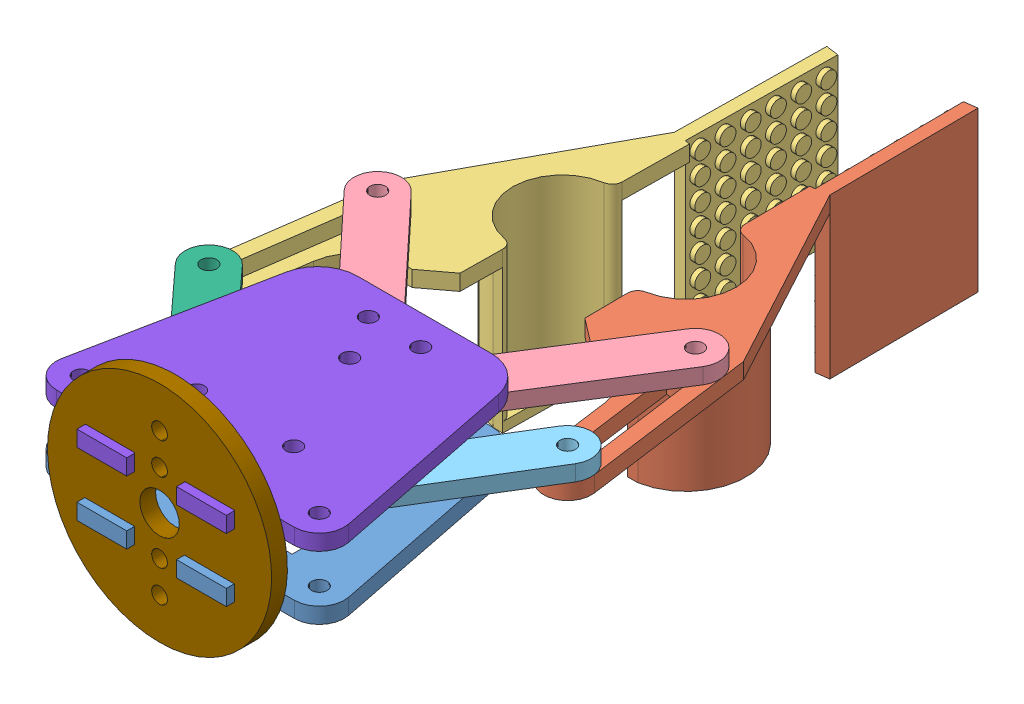
SolidWorks assembly Gripper, configuration Predeterminado. Lengths in mm.
Overall size (91.5 56.15 152.9).
15 component instances, 11 part files, 33 mates.
Components (placement in the parent):
- Base grip-1: Base grip [Predeterminado] at (-28.7905 -8.0804 25) size (57.8 3.17 54.76)
- Gripp4-3: Gripp4 [Predeterminado] at (19.4575 -1.7304 -56.7394) x (-0.990815 0 0.135226) z (0.135226 0 0.990815) size (24.38 32 109.52)
- Gripp3-3: Gripp3 [Predeterminado] at (-23.0143 -4.9054 -52.0769) x (0.99023 0 0.139447) z (-0.139447 0 0.99023) size (24.38 32 109.76)
- eslabon dos-1: eslabon dos [Predeterminado] at (13.1017 -1.7304 -38.4567) x (0.533516 0 -0.84579) z (0.84579 0 0.533516) size (49.52 3.17 9.53)
- eslabon dos-2: eslabon dos [Predeterminado] at (-14.2298 -1.7304 -36.8567) x (0.683322 0 0.730117) z (-0.730117 0 0.683322) size (49.52 3.17 9.53)
- eslabon engrane servo-1: eslabon engrane servo [Predeterminado] at (25.469 -1.7304 -3.5655) x (-0.522435 0 0.852679) z (-0.852679 0 -0.522435) size (56.02 3.17 23.48)
- eslabon engrane servo - copia-1: eslabon engrane servo - copia [Predeterminado] at (-18.5366 -1.7304 -6.9655) x (0.675407 0 0.737445) z (-0.737445 0 0.675407) size (56.51 3.17 22.67)
- separadores-1: separadores [Predeterminado] at (-8.5405 -4.9054 11) x (0.999665 0 -0.025874) z (0.025874 0 0.999665) size (6.35 3.17 6.35)
- separadores-2: separadores [Predeterminado] at (-8.5405 1.4446 11) x (0.999761 0 0.021872) z (-0.021872 0 0.999761) size (6.35 3.17 6.35)
- separadores-4: separadores [Predeterminado] at (-4.0405 -4.9054 -19) x (0.999761 0 0.021872) z (-0.021872 0 0.999761) size (6.35 3.17 6.35)
- separadores-5: separadores [Predeterminado] at (6.4595 1.4446 -19) x (0.999761 0 0.021872) z (-0.021872 0 0.999761) size (6.35 3.17 6.35)
- separadores-6: separadores [Predeterminado] at (-4.0405 1.4446 -19) x (0.999761 0 0.021872) z (-0.021872 0 0.999761) size (6.35 3.17 6.35)
- separadores-7: separadores [Predeterminado] at (6.4595 -4.9054 -19) x (0.999761 0 0.021872) z (-0.021872 0 0.999761) size (6.35 3.17 6.35)
- bse grip superior-2: bse grip superior [Predeterminado] at (-28.7905 4.6196 25) size (57.8 3.17 54.76)
- base gripper servo-1: base gripper servo [Predeterminado] at (1.2095 -0.0804 28.175) x (1 0 0) z (0 1 0) size (45 3.17 45)
Mates (geometry in assembly coordinates):
- Coincidente33: coincident aligned: axis of Base grip-1 through (-4.0405 -4.9054 -19) axis (0 -1 0); axis of eslabon dos-2 through (-4.0405 1.4446 -19) axis (0 -1 0)
- Coincidente38: coincident aligned: axis of Gripp3-3 through (-21.6955 -1.7304 -54.8929) axis (0 -1 0); axis of eslabon dos-2 through (-21.6955 1.4446 -54.8929) axis (0 -1 0)
- Coincidente43: coincident anti-aligned: axis of Gripp4-3 through (17.204 -4.9054 -57.5299) axis (0 1 0); axis of eslabon dos-1 through (17.204 1.4446 -57.5299) axis (0 -1 0)
- Coincidente44: coincident aligned: axis of Base grip-1 through (6.4595 -4.9054 -19) axis (0 -1 0); axis of eslabon dos-1 through (6.4595 1.4446 -19) axis (0 -1 0)
- Coincidente46: coincident anti-aligned: plane of Gripp3-3 through (-9.0404 -1.7304 -38.0769) normal (0 1 0); plane of eslabon dos-2 through (-21.6955 -1.7304 -54.8929) normal (0 -1 0)
- Coincidente49: coincident anti-aligned: plane of Gripp4-3 through (4.3823 -1.7304 -40.8406) normal (0 1 0); plane of eslabon dos-1 through (6.4595 -1.7304 -19) normal (0 -1 0)
- Coincidente55: coincident anti-aligned: axis of Gripp4-3 through (20.8649 -4.9054 -27.7541) axis (0 1 0); axis of eslabon engrane servo-1 through (20.8649 1.4446 -27.7541) axis (0 -1 0)
- Coincidente57: coincident anti-aligned: plane of Gripp4-3 through (4.3823 -1.7304 -40.8406) normal (0 1 0); plane of eslabon engrane servo-1 through (20.8649 -1.7304 -27.7541) normal (0 -1 0)
- Coincidente58: coincident aligned: axis of Gripp3-3 through (-25.6523 -1.7304 -25.155) axis (0 -1 0); axis of eslabon engrane servo - copia-1 through (-25.6523 1.4446 -25.155) axis (0 -1 0)
- Coincidente61: coincident anti-aligned: plane of Gripp3-3 through (-9.0404 -1.7304 -38.0769) normal (0 1 0); plane of eslabon engrane servo - copia-1 through (-25.6523 -1.7304 -25.155) normal (0 -1 0)
- Coincidente65: coincident anti-aligned: axis of eslabon engrane servo - copia-1 through (-8.5405 -1.7304 11) axis (0 1 0); axis of separadores-1 through (-8.5405 -1.7304 11) axis (0 -1 0)
- Coincidente66: coincident anti-aligned: plane of eslabon engrane servo - copia-1 through (-25.6523 -1.7304 -25.155) normal (0 -1 0); plane of separadores-1 through (-8.5405 -1.7304 11) normal (0 1 0)
- Coincidente67: coincident: moEndPointRef_w of separadores-1; axis of separadores-2 through (-8.5405 4.6196 11) axis (0 -1 0)
- Coincidente68: coincident anti-aligned: plane of eslabon engrane servo - copia-1 through (-25.6523 1.4446 -25.155) normal (0 1 0); plane of separadores-2 through (-8.5405 1.4446 11) normal (0 -1 0)
- Coincidente69: coincident aligned: axis of eslabon dos-2 through (-4.0405 1.4446 -19) axis (0 -1 0); axis of separadores-4 through (-4.0405 -1.7304 -19) axis (0 -1 0)
- Coincidente70: coincident anti-aligned: plane of eslabon dos-2 through (-21.6955 -1.7304 -54.8929) normal (0 -1 0); plane of separadores-4 through (-4.0405 -1.7304 -19) normal (0 1 0)
- Coincidente71: coincident anti-aligned: plane of Base grip-1 through (14.651 -4.9054 -17) normal (0 1 0); plane of separadores-4 through (-4.0405 -4.9054 -19) normal (0 -1 0)
- Coincidente72: coincident anti-aligned: plane of eslabon dos-1 through (6.4595 -1.7304 -19) normal (0 -1 0); plane of separadores-7 through (6.4595 -1.7304 -19) normal (0 1 0)
- Coincidente74: coincident aligned: axis of eslabon dos-1 through (6.4595 1.4446 -19) axis (0 -1 0); axis of separadores-7 through (6.4595 -1.7304 -19) axis (0 -1 0)
- Coincidente77: coincident anti-aligned: plane of eslabon dos-2 through (-21.6955 1.4446 -54.8929) normal (0 1 0); plane of separadores-6 through (-4.0405 1.4446 -19) normal (0 -1 0)
- Coincidente78: coincident aligned: axis of eslabon dos-2 through (-4.0405 1.4446 -19) axis (0 -1 0); axis of separadores-6 through (-4.0405 4.6196 -19) axis (0 -1 0)
- Coincidente79: coincident anti-aligned: plane of eslabon dos-1 through (6.4595 1.4446 -19) normal (0 1 0); plane of separadores-5 through (6.4595 1.4446 -19) normal (0 -1 0)
- Coincidente80: coincident aligned: axis of eslabon dos-1 through (6.4595 1.4446 -19) axis (0 -1 0); axis of separadores-5 through (6.4595 4.6196 -19) axis (0 -1 0)
- Coincidente81: coincident anti-aligned: plane of Base grip-1 through (14.651 -4.9054 -17) normal (0 1 0); plane of separadores-7 through (6.4595 -4.9054 -19) normal (0 -1 0)
- Coincidente82: coincident aligned: axis of Base grip-1 through (-8.5405 -4.9054 11) axis (0 -1 0); axis of separadores-2 through (-8.5405 4.6196 11) axis (0 -1 0)
- Coincidente83: coincident aligned: axis of Base grip-1 through (-22.6915 -8.0804 20) axis (0 1 0); axis of bse grip superior-2 through (-22.6915 4.6196 20) axis (0 1 0)
- Coincidente84: coincident aligned: axis of Base grip-1 through (1.2095 -8.0804 -10) axis (0 1 0); axis of bse grip superior-2 through (1.2095 4.6196 -10) axis (0 1 0)
- Coincidente85: coincident anti-aligned: axis of eslabon engrane servo-1 through (10.9595 -1.7304 11) axis (0 1 0); axis of bse grip superior-2 through (10.9595 7.7946 11) axis (0 -1 0)
- Coincidente86: coincident anti-aligned: plane of separadores-2 through (-8.5405 4.6196 11) normal (0 1 0); plane of bse grip superior-2 through (14.651 4.6196 -17) normal (0 -1 0)
- Relación de posición de engranaje7: gear = 15 : 15 mm: axis of eslabon engrane servo - copia-1 through (-8.5405 -1.7304 11) axis (0 1 0); axis of eslabon engrane servo-1 through (10.9595 -1.7304 11) axis (0 1 0)
- Coincidente93: coincident anti-aligned: plane of Base grip-1 through (-28.7905 -4.9054 25) normal (0 0 1); plane of base gripper servo-1 through (1.2095 -0.0804 25) normal (0 0 -1)
- Coincidente94: coincident anti-aligned: plane of Base grip-1 through (-3.7905 -8.0804 25) normal (1 0 0); plane of base gripper servo-1 through (-3.7905 -8.0804 25) normal (-1 0 0)
- Coincidente95: coincident anti-aligned: plane of Base grip-1 through (14.651 -8.0804 -17) normal (0 -1 0); plane of base gripper servo-1 through (-13.7905 -8.0804 25) normal (0 1 0)
